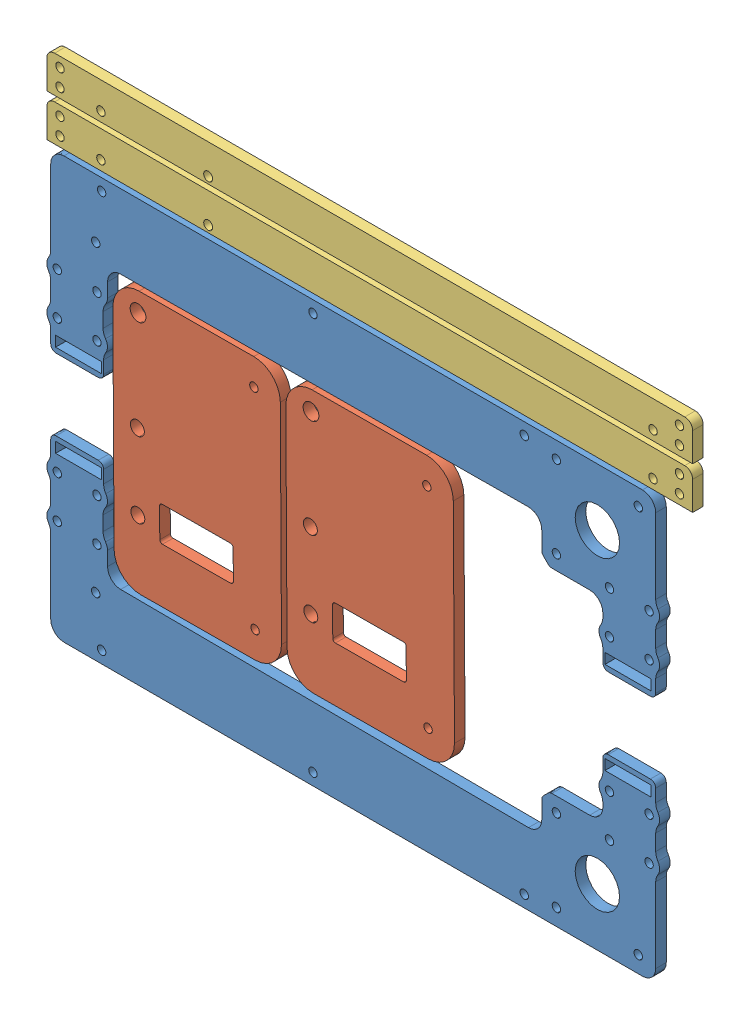
SolidWorks assembly X FRAME, configuration Default. Lengths in mm.
Overall size (250 200 4).
7 component instances, 4 part files, 27 mates.
Components (placement in the parent):
- X Bridge 4-1: X Bridge 4 [Valor predeterminado] at (-97.88 -11.4267 0) size (232 66.16 4)
- X Bridge 4-2: X Bridge 4 [Valor predeterminado] at (-97.88 -2.0391 4) x (1 0 0) z (0 0 -1) size (232 66.16 4)
- Small foot2-4: Small foot2 [Default] at (-232.4394 -324.5343 0) x (-0.999984 -0.00574 0) z (0 0 1) size (63.38 99.24 4)
- Small foot2-5: Small foot2 [Default] at (-166.9563 -324.1584 0) x (-0.999984 -0.00574 0) z (0 0 1) size (63.38 99.24 4)
- CONECTION-1: CONECTION [Default] at (-270.2307 -22.6802 0) x (0 1 0) z (0 0 1) (suppressed, hidden)
- Handle-1: Handle [Default] at (-32.5 15.508 0) size (244.5 13.87 4)
- Handle-2: Handle [Default] at (-32.5 -0.4578 0) size (244.5 13.87 4)
Mates (geometry in assembly coordinates):
- Parallel3: parallel anti-aligned: plane of X Bridge 4-2 through (-70.88 -100.5949 0) normal (0 -1 0); plane of Small foot2-5
- Coincident15: coincident anti-aligned: plane of X Bridge 4-1 through (-97.88 -11.4267 0) normal (0 0 -1); plane of assembly through (0 0 0) normal (0 0 1)
- Coincident17: coincident aligned: plane of X Bridge 4-1 through (-97.88 -11.4267 4) normal (0 0 1); plane of Small foot2-4 through (-232.4394 -324.5343 4) normal (0 0 1)
- Parallel4: parallel anti-aligned: plane of X Bridge 4-1 through (-97.88 72.9814 4) normal (0 1 0); plane of Handle-2 through (30.0711 75.0814 4) normal (0 -1 0)
- Coincident20: coincident anti-aligned: line of ? through (219.0037 38.0748 99.4051) axis (0 -1 0)
- Parallel5: parallel aligned: line of assembly; line of X Bridge 4-2 through (-212.9289 -81.4472 0) axis (0 1 0)
- Coincident27: coincident aligned: plane of X Bridge 4-1 through (-97.88 -11.4267 0) normal (0 0 -1); plane of X Bridge 4-2 through (-97.88 -2.0391 0) normal (0 0 -1)
- Distance19: distance = 1 mm: cylinder of X Bridge 4-1 through (-210.4289 18.5906 4) axis (0 0 -1) radius 4; line of assembly
- Coincident33: coincident aligned: plane of X Bridge 4-1 through (-97.88 -11.4267 4) normal (0 0 1); plane of Small foot2-5 through (-166.9563 -324.1584 4) normal (0 0 1)
- Distance5: distance = 2 mm anti-aligned: plane of Small foot2-4 through (-106.6664 -53.0476 4) normal (0.999984 0.00574 0); plane of Small foot2-5 through (-41.7529 46.5663 4) normal (-0.00574 0.999984 0)
- Coincident38: coincident aligned: plane of X Bridge 4-1 through (-97.88 -11.4267 0) normal (0 0 -1); plane of CONECTION-1 through (-270.2307 -22.6802 0) normal (0 0 -1)
- Parallel6: parallel anti-aligned: plane of Small foot2-4 through (-125.5152 -56.0468 4) normal (0.999984 0.00574 0); plane of Small foot2-5 through (-123.4152 -56.0347 4) normal (-0.999984 -0.00574 0)
- Distance9: distance = 2.1 mm anti-aligned: plane of Small foot2-5 through (-123.4152 -56.0347 4) normal (-0.999984 -0.00574 0); plane of Small foot2-4 through (-125.5152 -56.0468 4) normal (0.999984 0.00574 0)
- Coincident45: coincident aligned: plane of X Bridge 4-1 through (-97.88 -11.4267 4) normal (0 0 1); plane of Handle-1 through (27.0711 101.9131 4) normal (0 0 1)
- Distance17: distance = 1 mm: plane of Handle-1 through (-214.4289 101.9131 4) normal (-1 0 0); line of assembly
- Distance10: distance = 2.1 mm anti-aligned: plane of Handle-2 through (27.0711 88.9473 4) normal (0 1 0); plane of Handle-1 through (30.0711 91.0473 4) normal (0 -1 0)
- Coincident49: coincident aligned: plane of Handle-1 through (27.0711 101.9131 4) normal (0 0 1); plane of Handle-2 through (27.0711 85.9473 4) normal (0 0 1)
- Coincident50: coincident aligned: plane of Handle-1 through (-214.4289 101.9131 4) normal (-1 0 0); plane of Handle-2 through (-214.4289 85.9473 4) normal (-1 0 0)
- Coincident51: coincident aligned: plane of Small foot2-4 through (-125.5152 -56.0468 4) normal (0.00574 -0.999984 0); plane of Small foot2-5 through (-60.032 -55.6709 4) normal (0.00574 -0.999984 0)
- Distance11: distance = 2.1 mm anti-aligned: plane of X Bridge 4-1 through (-97.88 72.9814 4) normal (0 1 0); plane of Handle-2 through (30.0711 75.0814 4) normal (0 -1 0)
- Distance13: distance = 2.1 mm anti-aligned: plane of Small foot2-4 through (-126.0848 43.1912 4) normal (-0.00574 0.999984 0); plane of X Bridge 4-1 through (-98.2065 45.4513 4) normal (0.00574 -0.999984 0)
- Distance14: distance = 2.1 mm anti-aligned: cylinder of X Bridge 4-1 through (13.5748 18.5906 4) axis (0 0 -1) radius 4; plane of CONECTION-1 through (19.6748 -85.9992 4) normal (-1 0 0)
- Distance20: distance = 1 mm: cylinder of X Bridge 4-2 through (-210.4289 -48.0564 0) axis (0 0 1) radius 4; line of assembly
- Distance15: distance = 2.1 mm anti-aligned: cylinder of Small foot2-4 through (-178.9559 -46.3534 4) axis (0 0 -1) radius 10; plane of X Bridge 4-2 through (-98.2065 -58.9171 0) normal (0.00574 0.999984 0)
- Distance16: distance = 2.1 mm anti-aligned: plane of CONECTION-1 through (19.6748 72.9814 4) normal (0 1 0); plane of Handle-2 through (30.0711 75.0814 4) normal (0 -1 0)
- Distance21: distance = 1 mm: plane of Handle-1 through (27.0711 104.9131 4) normal (0 1 0); line of assembly
- Distance22: distance = 2.1 mm anti-aligned: plane of Small foot2-4 through (-188.8983 -56.4106 4) normal (-0.999984 -0.00574 0); cylinder of X Bridge 4-1 through (-195.4289 18.5906 4) axis (0 0 -1) radius 4
